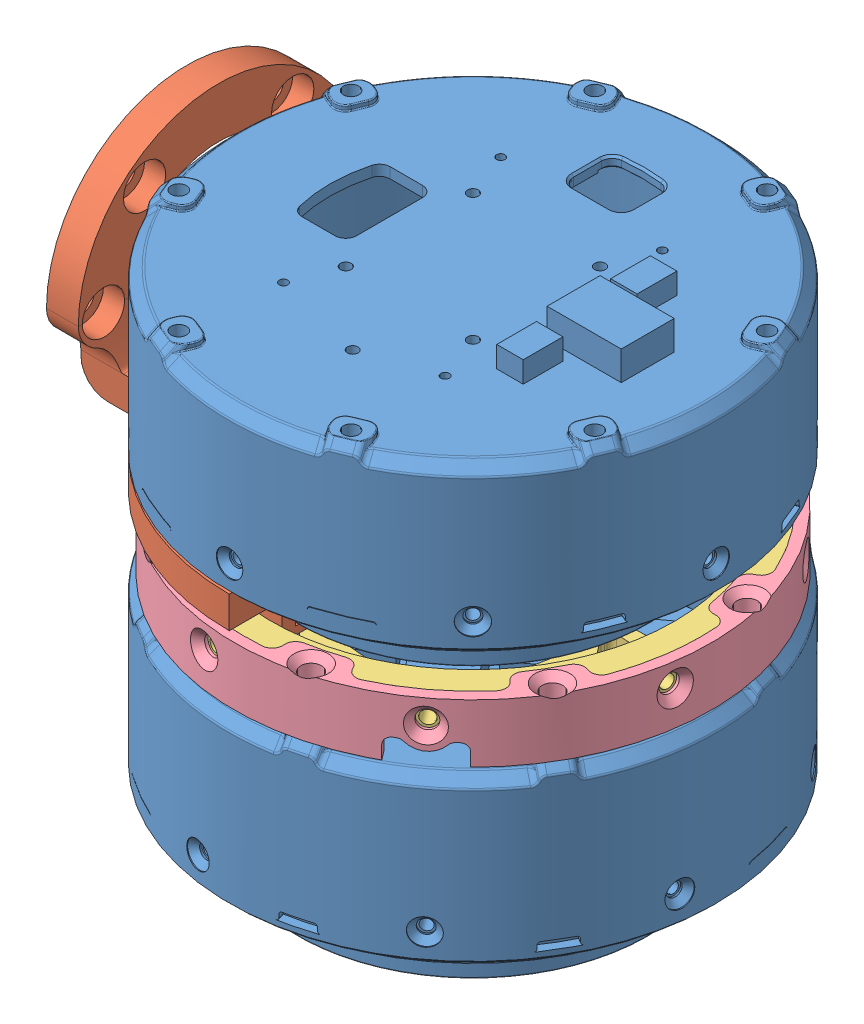
SolidWorks assembly 髋关节, configuration 默认. Lengths in mm.
Overall size (130.12 101.02 130.12).
10 component instances, 5 part files, 16 mates.
Components (placement in the parent):
- 动力单元组件-1: 动力单元组件 [默认] at (13.1809 -106.7846 -0.9804) x (-0.707107 0 -0.707107) z (0 -1 0) size (92.01 92.01 49.55)
- 髋部支架_L型后支架-1: 髋部支架_L型后支架 [默认] at (13.1809 -106.2946 -0.9804) x (1 0 0) z (0 -1 0) size (54 92 49.47)
- 髋部关节组件_股关节连接-1: 髋部关节组件_股关节连接 [默认] at (13.1809 -117.7846 -0.9804) x (-0.60139 0 -0.798955) z (0 -1 0) size (86 86 9)
- 髋部关节组件_肘部电机连接件-1: 髋部关节组件_肘部电机连接件 [默认] at (13.1809 -122.7846 -0.9804) x (0.798955 0 -0.60139) z (0 -1 0) size (90 90 11.26)
- 动力单元组件-2: 动力单元组件 [默认] at (13.1809 -157.8346 -0.9804) x (0.139699 0 -0.990194) z (0 -1 0) size (92.01 92.01 49.55)
- 垫片-1: 垫片 [默认] at (18.0848 -117.7846 -22.1703) x (-0.837169 0 -0.546944) z (0 1 0) size (6 6 1)
- 垫片-2: 垫片 [默认] at (34.9005 -117.7846 0.1695) x (-0.837169 0 -0.546944) z (0 1 0) size (6 6 1)
- 垫片-3: 垫片 [默认] at (0.1006 -117.7846 -18.3577) x (-0.837169 0 -0.546944) z (0 1 0) size (6 6 1)
- 垫片-4: 垫片 [默认] at (-8.5387 -117.7846 -2.1302) x (-0.837169 0 -0.546944) z (0 1 0) size (6 6 1)
- 垫片-5: 垫片 [默认] at (8.2769 -117.7846 20.2095) x (-0.837169 0 -0.546944) z (0 1 0) size (6 6 1)
Mates (geometry in assembly coordinates):
- 同心1: concentric aligned: circle of 动力单元组件-1; circle of 髋部支架_L型后支架-1
- 重合13: coincident anti-aligned: plane of 动力单元组件-1 through (36.5154 -114.7846 -24.3149) normal (0 -1 0); plane of 髋部支架_L型后支架-1 through (13.1809 -114.7846 -0.9804) normal (0 1 0)
- 同心2: concentric aligned: cylinder of 动力单元组件-1 through (3.6046 -106.2846 34.7589) axis (0 -1 0) radius 1.25; cylinder of 髋部支架_L型后支架-1 through (3.6046 -109.2946 34.7589) axis (0 -1 0) radius 1.25
- 距离2: distance = 1 mm anti-aligned: plane of 动力单元组件-1 through (13.1809 -116.7846 -0.9804) normal (0 -1 0); plane of 髋部关节组件_股关节连接-1 through (13.1809 -117.7846 -0.9804) normal (0 1 0)
- 同心3: concentric aligned: circle of 动力单元组件-1; circle of 髋部关节组件_股关节连接-1
- 同心5: concentric aligned: circle of 髋部关节组件_股关节连接-1; circle of 髋部关节组件_肘部电机连接件-1
- 同心6: concentric aligned: cylinder of 髋部关节组件_股关节连接-1 through (39.0407 -116.2846 33.3747) axis (0.60139 0 0.798955) radius 1.25; cylinder of 髋部关节组件_肘部电机连接件-1 through (40.2435 -116.2846 34.9726) axis (0.60139 0 0.798955) radius 1.7
- 重合5: coincident anti-aligned: plane of 髋部关节组件_肘部电机连接件-1 through (13.1809 -122.7846 -0.9804) normal (0 -1 0); plane of 动力单元组件-2 through (13.1809 -122.7846 -0.9804) normal (0 1 0)
- 平行1: parallel aligned: line of 髋部关节组件_股关节连接-1 through (17.9063 -120.7846 13.6114) axis (0.798955 0 -0.60139); line of 动力单元组件-2 through (29.032 -118.2846 28.3921) axis (0.798955 0 -0.60139)
- 同心7: concentric anti-aligned: cylinder of 髋部关节组件_肘部电机连接件-1 through (49.7887 -111.7846 20.6094) axis (0 1 0) radius 1.95; cylinder of 动力单元组件-2 through (49.7887 -127.2846 20.6094) axis (0 -1 0) radius 1.45
- 重合6: coincident aligned: plane of 髋部关节组件_股关节连接-1 through (13.1809 -117.7846 -0.9804) normal (0 1 0); circle of 垫片-1
- 重合7: coincident aligned: circle of 髋部关节组件_股关节连接-1; circle of 垫片-1
- 重合8: coincident aligned: circle of 髋部关节组件_股关节连接-1; circle of 垫片-2
- 重合10: coincident aligned: circle of 髋部关节组件_股关节连接-1; circle of 垫片-3
- 重合11: coincident aligned: circle of 髋部关节组件_股关节连接-1; circle of 垫片-4
- 重合12: coincident aligned: circle of 髋部关节组件_股关节连接-1; circle of 垫片-5
